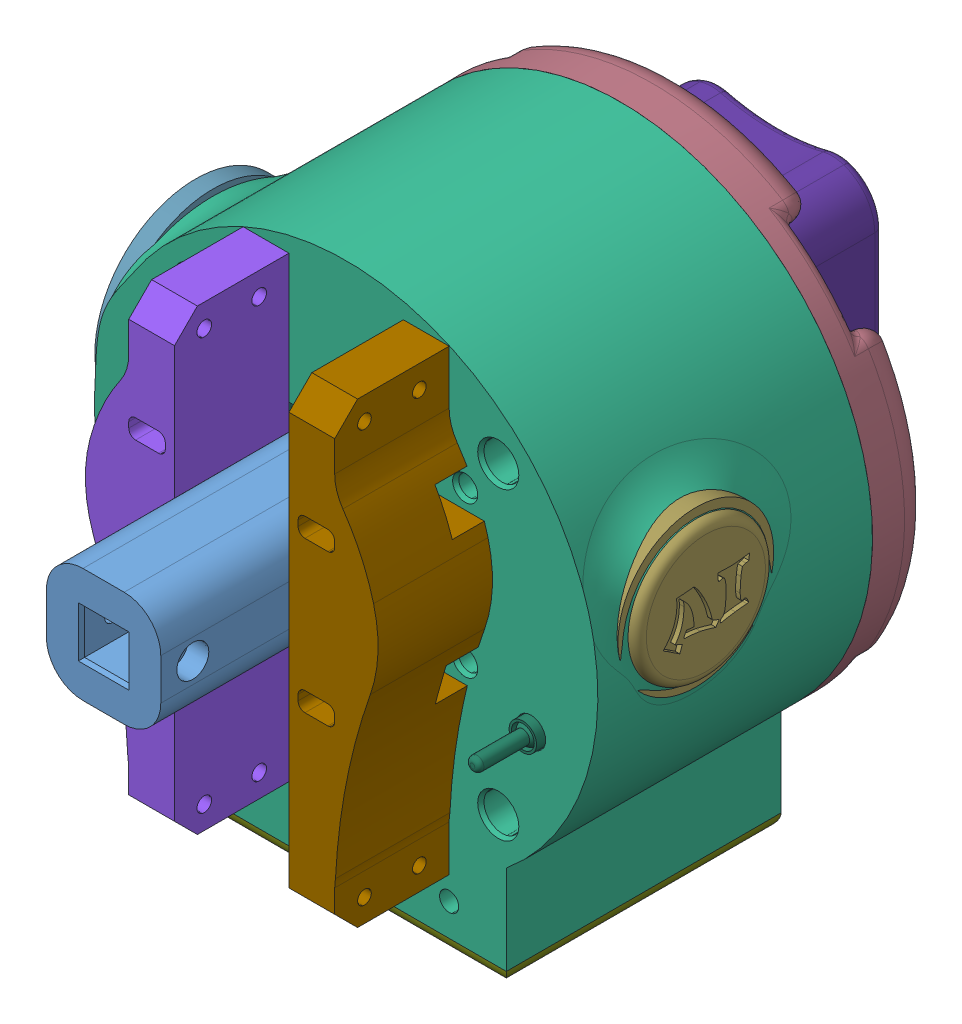
SolidWorks assembly clb00_CollectiveBaseI2C, configuration По умолчанию. Lengths in mm.
Overall size (115.55 120 148).
24 component instances, 17 part files, 56 mates.
Components (placement in the parent):
- clb03a_LeverConnector10mmRail-1: clb03a_LeverConnector10mmRail [По умолчанию] at (44.3103 52.5722 -4.4772) size (25 25 86)
- 608_bearing_v1-1: 608_bearing_v1 [По умолчанию] at (58.4103 52.5722 5.5228) x (0 -0.975622 0.219457) z (0 0.219457 0.975622) size (22 7.15 22)
- 608_bearing_v1-2: 608_bearing_v1 [По умолчанию] at (16.3103 52.5722 5.5228) x (0 -1 0) z (0 0 1) size (22 7.15 22)
- 608_bearing_v1-3: 608_bearing_v1 [По умолчанию] at (72.3103 52.5722 5.5228) x (0 1 0) z (0 0 1) size (22 7.15 22)
- 608_bearing_v1-4: 608_bearing_v1 [По умолчанию] at (30.2103 52.5722 5.5228) x (0 1 0) z (0 0 1) size (22 7.15 22)
- M8 washer_regular-1: M8 washer_regular [По умолчанию] at (31.8103 52.5722 5.5228) x (0 0 1) z (-1 0 0) size (15.8 15.8 1.5)
- M8 washer_regular-2: M8 washer_regular [По умолчанию] at (58.3103 52.5722 5.5228) x (0 0 1) z (-1 0 0) size (15.8 15.8 1.5)
- clb01_LeverFrameP1-3: clb01_LeverFrameP1 [По умолчанию] at (44.3103 52.5722 20.5228) x (1 0 0) z (0 1 0) size (78.5 15 68)
- M6x70mm-1: M6x70mm [По умолчанию] at (5.4103 52.5722 5.5228) x (0 -0.980406 -0.196989) z (0 -0.196989 0.980406) size (11.6 74.3 11.6)
- clb05_EnclosureWExtSlot-1: clb05_EnclosureWExtSlot [По умолчанию] at (44.3103 44.0722 -32.4772) x (0 1 0) z (1 0 0) size (117 62.47 113.55)
- clb02_LeverFrameP2-2: clb02_LeverFrameP2 [По умолчанию] at (44.3103 52.5722 -9.4772) x (-1 0 0) z (0 1 0) size (65 15 68)
- clb10_FrictionTensionerLeft-1: clb10_FrictionTensionerLeft [По умолчанию] at (21.8103 44.2222 27.5228) x (1 0 0) z (0 -1 0) size (19.47 25 100)
- clb11_FrictionTensionerRight-1: clb11_FrictionTensionerRight [По умолчанию] at (66.8103 44.1222 52.5228) x (-1 0 0) z (0 -1 0) size (19.47 25 100)
- 6x6x4mm_square-1: 6x6x4mm_square [По умолчанию] at (2.4103 49.5722 5.5228) size (6 6 4)
- M8 washer_regular-3: M8 washer_regular [По умолчанию] at (72.4103 52.5722 5.5228) x (0 0 -1) z (1 0 0) size (15.8 15.8 1.5)
- M8 washer_regular-4: M8 washer_regular [По умолчанию] at (75.4103 52.5722 5.5228) x (0 0 1) z (-1 0 0) size (15.8 15.8 1.5)
- clb04_LeverFrameCurtain-1: clb04_LeverFrameCurtain [По умолчанию] at (42.9159 43.7468 -9.4772) x (1 0 0) z (0 0 -1) size (65 54.8 2.4)
- clb08_CalibrationScrewLid-1: clb08_CalibrationScrewLid [По умолчанию] at (95.4103 52.0722 6.0228) x (0 0.9998 0.019984) z (0 0.019984 -0.9998) size (34 6 34)
- clb06_EnclosureBackI2C-1: clb06_EnclosureBackI2C [По умолчанию] at (44.3103 44.0722 -45.4772) x (0 1 0) z (1 0 0) size (110 19.51 110)
- clb07_EnclosureSensorLid-1: clb07_EnclosureSensorLid [По умолчанию] at (-6.7897 54.0722 5.5228) x (0 0.999914 0.013101) z (0 -0.013101 0.999914) size (44 6 44)
- MTS-103-1: MTS-103 [По умолчанию] at (3.9103 30.0722 11.0228) x (0 -1 0) z (-1 0 0) size (13.2 33.3 7.9)
- MTS-103-2: MTS-103 [По умолчанию] at (84.7103 30.0722 11.0228) x (0 1 0) z (1 0 0) size (13.2 33.3 7.9)
- clb09_ExtSlotLid-2: clb09_ExtSlotLid [По умолчанию] at (44.3103 4.0722 -2.4772) x (-1 0 0) z (0 0 1) size (70 25 60)
- clb12_RailMount-1: clb12_RailMount [По умолчанию] at (44.3103 44.0722 -45.4772) x (1 0 0) z (0 1 0) size (45 22 69.79)
Mates (geometry in assembly coordinates):
- Concentric1: concentric anti-aligned: cylinder of clb03a_LeverConnector10mmRail-1 through (56.8103 52.5722 5.5228) axis (-1 0 0) radius 3; cylinder of 608_bearing_v1-4 through (26.7353 52.5722 5.5228) axis (1 0 0) radius 4
- Concentric2: concentric anti-aligned: cylinder of 608_bearing_v1-2 through (19.7853 52.5722 5.5228) axis (-1 0 0) radius 4; cylinder of 608_bearing_v1-4 through (26.7353 52.5722 5.5228) axis (1 0 0) radius 4
- Coincident1: coincident anti-aligned: plane of 608_bearing_v1-2 through (23.2603 52.5722 5.5228) normal (1 0 0); plane of 608_bearing_v1-4 through (23.2603 52.5722 5.5228) normal (-1 0 0)
- Concentric3: concentric anti-aligned: cylinder of clb03a_LeverConnector10mmRail-1 through (56.8103 52.5722 5.5228) axis (-1 0 0) radius 3; cylinder of 608_bearing_v1-3 through (68.8353 52.5722 5.5228) axis (1 0 0) radius 4
- Concentric4: concentric anti-aligned: cylinder of 608_bearing_v1-1 through (61.8853 52.5722 5.5228) axis (-1 0 0) radius 4; cylinder of 608_bearing_v1-3 through (68.8353 52.5722 5.5228) axis (1 0 0) radius 4
- Coincident2: coincident anti-aligned: plane of 608_bearing_v1-1 through (65.3603 52.5722 5.5228) normal (1 0 0); plane of 608_bearing_v1-3 through (65.3603 52.5722 5.5228) normal (-1 0 0)
- Concentric6: concentric anti-aligned: cylinder of clb03a_LeverConnector10mmRail-1 through (56.8103 52.5722 5.5228) axis (-1 0 0) radius 3; cylinder of M8 washer_regular-2 through (56.8103 52.5722 5.5228) axis (1 0 0) radius 4.15
- Coincident5: coincident anti-aligned: plane of clb03a_LeverConnector10mmRail-1 through (56.8103 40.0722 80.5228) normal (1 0 0); plane of M8 washer_regular-2 through (56.8103 52.5722 5.5228) normal (-1 0 0)
- Concentric7: concentric anti-aligned: cylinder of clb03a_LeverConnector10mmRail-1 through (56.8103 52.5722 5.5228) axis (-1 0 0) radius 3; cylinder of M8 washer_regular-1 through (30.3103 52.5722 5.5228) axis (1 0 0) radius 4.15
- Coincident6: coincident anti-aligned: plane of clb03a_LeverConnector10mmRail-1 through (31.8103 40.0722 80.5228) normal (-1 0 0); plane of M8 washer_regular-1 through (31.8103 52.5722 5.5228) normal (1 0 0)
- Coincident7: coincident anti-aligned: plane of 608_bearing_v1-4 through (30.3103 52.5722 5.5228) normal (1 0 0); plane of M8 washer_regular-1 through (30.3103 52.5722 5.5228) normal (-1 0 0)
- Coincident8: coincident anti-aligned: plane of 608_bearing_v1-1 through (58.3103 52.5722 5.5228) normal (-1 0 0); plane of M8 washer_regular-2 through (58.3103 52.5722 5.5228) normal (1 0 0)
- Concentric10: concentric aligned: cylinder of 608_bearing_v1-2 through (19.7853 52.5722 5.5228) axis (-1 0 0) radius 11; cylinder of clb01_LeverFrameP1-3 through (58.3103 52.5722 5.5228) axis (-1 0 0) radius 11.1
- Coincident9: coincident anti-aligned: plane of 608_bearing_v1-2 through (16.3103 52.5722 5.5228) normal (-1 0 0); plane of clb01_LeverFrameP1-3 through (16.3103 63.6722 5.5228) normal (1 0 0)
- Angle4: planar angle = 0 rad anti-aligned: plane of clb03a_LeverConnector10mmRail-1 through (56.8103 65.0722 80.5228) normal (0 1 0); plane of clb01_LeverFrameP1-3 through (89.3722 65.3722 11.4363) normal (0 -1 0)
- Concentric14: concentric anti-aligned: cylinder of 608_bearing_v1-3 through (68.8353 52.5722 5.5228) axis (1 0 0) radius 4; cylinder of M6x70mm-1 through (75.4103 52.5722 5.5228) axis (-1 0 0) radius 3
- Parallel1: parallel anti-aligned: plane of clb03a_LeverConnector10mmRail-1 through (31.8103 40.0722 80.5228) normal (-1 0 0); plane of clb05_EnclosureWExtSlot-1 through (31.3103 23.4722 27.5228) normal (1 0 0)
- Coincident15: coincident anti-aligned: plane of clb01_LeverFrameP1-3 through (44.3103 52.5722 20.5228) normal (0 0 1); plane of clb05_EnclosureWExtSlot-1 through (44.3103 44.0722 20.5228) normal (0 0 -1)
- Concentric15: concentric aligned: cylinder of 608_bearing_v1-3 through (68.8353 52.5722 5.5228) axis (1 0 0) radius 11; cylinder of clb02_LeverFrameP2-2 through (30.3103 52.5722 5.5228) axis (1 0 0) radius 11.1
- Concentric16: concentric anti-aligned: cylinder of clb01_LeverFrameP1-3 through (18.3103 36.0722 20.5228) axis (0 0 -1) radius 2.15; cylinder of clb02_LeverFrameP2-2 through (18.3103 36.0722 -9.4772) axis (0 0 1) radius 2.15
- Coincident18: coincident anti-aligned: plane of clb03a_LeverConnector10mmRail-1 through (31.8103 40.0722 80.5228) normal (-1 0 0); plane of clb10_FrictionTensionerLeft-1 through (31.8103 -5.7778 52.5228) normal (1 0 0)
- Coincident19: coincident anti-aligned: plane of clb05_EnclosureWExtSlot-1 through (44.3103 44.0722 27.5228) normal (0 0 1); plane of clb10_FrictionTensionerLeft-1 through (21.8103 44.2222 27.5228) normal (0 0 -1)
- Tangent1: tangent anti-aligned: cylinder of clb05_EnclosureWExtSlot-1 through (26.3103 36.0722 -32.4772) axis (0 0 1) radius 2.25; plane of clb10_FrictionTensionerLeft-1 through (29.8103 38.3222 52.5228) normal (0 -1 0)
- Concentric18: concentric aligned: cylinder of clb05_EnclosureWExtSlot-1 through (18.3103 69.0722 -32.4772) axis (0 0 1) radius 2.25; cylinder of clb02_LeverFrameP2-2 through (18.3103 69.0722 -9.4772) axis (0 0 1) radius 2.15
- Coincident20: coincident anti-aligned: plane of clb05_EnclosureWExtSlot-1 through (44.3103 44.0722 27.5228) normal (0 0 1); plane of clb11_FrictionTensionerRight-1 through (66.8103 44.1222 27.5228) normal (0 0 -1)
- Coincident21: coincident anti-aligned: plane of clb03a_LeverConnector10mmRail-1 through (56.8103 40.0722 80.5228) normal (1 0 0); plane of clb11_FrictionTensionerRight-1 through (56.8103 -5.8778 27.5228) normal (-1 0 0)
- Tangent2: tangent anti-aligned: cylinder of clb01_LeverFrameP1-3 through (62.3103 36.0722 20.5228) axis (0 0 -1) radius 2.15; plane of clb11_FrictionTensionerRight-1 through (58.8103 38.2222 27.5228) normal (0 -1 0)
- Coincident23: coincident anti-aligned: plane of M6x70mm-1 through (5.4103 52.5722 5.5228) normal (-1 0 0); plane of 6x6x4mm_square-1 through (5.4103 55.5722 7.5228) normal (1 0 0)
- Concentric21: concentric anti-aligned: cylinder of M6x70mm-1 through (75.4103 52.5722 5.5228) axis (-1 0 0) radius 3; cylinder of 6x6x4mm_square-1 through (4.4103 52.5722 5.5228) axis (1 0 0) radius 1.5
- Concentric22: concentric anti-aligned: cylinder of M6x70mm-1 through (75.4103 52.5722 5.5228) axis (-1 0 0) radius 3; cylinder of M8 washer_regular-4 through (73.9103 52.5722 5.5228) axis (1 0 0) radius 4.15
- Concentric23: concentric anti-aligned: cylinder of M8 washer_regular-3 through (73.9103 52.5722 5.5228) axis (-1 0 0) radius 4.15; cylinder of M8 washer_regular-4 through (73.9103 52.5722 5.5228) axis (1 0 0) radius 4.15
- Coincident24: coincident anti-aligned: plane of M8 washer_regular-3 through (73.9103 52.5722 5.5228) normal (1 0 0); plane of M8 washer_regular-4 through (73.9103 52.5722 5.5228) normal (-1 0 0)
- Coincident25: coincident anti-aligned: plane of 608_bearing_v1-3 through (72.4103 52.5722 5.5228) normal (1 0 0); plane of M8 washer_regular-3 through (72.4103 52.5722 5.5228) normal (-1 0 0)
- Coincident26: coincident anti-aligned: plane of M6x70mm-1 through (75.4103 52.5722 5.5228) normal (-1 0 0); plane of M8 washer_regular-4 through (75.4103 52.5722 5.5228) normal (1 0 0)
- Concentric28: concentric aligned: cylinder of clb02_LeverFrameP2-2 through (18.3103 21.0722 -9.4772) axis (0 0 1) radius 2.15; cylinder of clb04_LeverFrameCurtain-1 through (18.3103 21.0722 -11.8772) axis (0 0 1) radius 2.15
- Concentric29: concentric aligned: cylinder of clb02_LeverFrameP2-2 through (70.3103 21.0722 -9.4772) axis (0 0 1) radius 2.15; cylinder of clb04_LeverFrameCurtain-1 through (70.3103 21.0722 -11.8772) axis (0 0 1) radius 2.15
- Coincident28: coincident anti-aligned: plane of clb02_LeverFrameP2-2 through (44.3103 52.5722 -9.4772) normal (0 0 -1); plane of clb04_LeverFrameCurtain-1 through (42.9159 43.7468 -9.4772) normal (0 0 1)
- Concentric40: concentric aligned: cylinder of clb05_EnclosureWExtSlot-1 through (44.3103 44.0722 17.5228) axis (0 0 -1) radius 50; cylinder of clb06_EnclosureBackI2C-1 through (44.3103 44.0722 -32.4772) axis (0 0 -1) radius 55
- Concentric41: concentric anti-aligned: cylinder of clb05_EnclosureWExtSlot-1 through (77.5444 10.8382 -32.4772) axis (0 0 1) radius 4; cylinder of clb06_EnclosureBackI2C-1 through (77.5444 10.8382 -27.4772) axis (0 0 -1) radius 4.1
- Coincident45: coincident anti-aligned: plane of clb05_EnclosureWExtSlot-1 through (44.3103 44.0722 -32.4772) normal (0 0 -1); plane of clb06_EnclosureBackI2C-1 through (44.3103 44.0722 -32.4772) normal (0 0 1)
- Concentric42: concentric aligned: cylinder of clb05_EnclosureWExtSlot-1 through (99.3103 52.0722 6.0228) axis (-1 0 0) radius 12.5; cylinder of clb08_CalibrationScrewLid-1 through (99.4103 52.0722 6.0228) axis (-1 0 0) radius 12.3
- Coincident47: coincident anti-aligned: plane of clb05_EnclosureWExtSlot-1 through (99.4103 52.0722 6.0228) normal (1 0 0); plane of clb08_CalibrationScrewLid-1 through (99.4103 52.0722 6.0228) normal (-1 0 0)
- Concentric44: concentric anti-aligned: cylinder of clb05_EnclosureWExtSlot-1 through (11.3103 54.0722 5.5228) axis (-1 0 0) radius 17.5; cylinder of clb07_EnclosureSensorLid-1 through (-10.7897 54.0722 5.5228) axis (1 0 0) radius 17.3
- Coincident48: coincident anti-aligned: plane of clb05_EnclosureWExtSlot-1 through (-10.7897 54.0722 5.5228) normal (-1 0 0); plane of clb07_EnclosureSensorLid-1 through (-10.7897 54.0722 5.5228) normal (1 0 0)
- Concentric45: concentric aligned: cylinder of clb05_EnclosureWExtSlot-1 through (3.9103 30.0722 29.9925) axis (0 0 -1) radius 3.2; cylinder of MTS-103-1 through (3.9103 30.0722 29.3228) axis (0 0 -1) radius 3
- Concentric46: concentric aligned: cylinder of clb05_EnclosureWExtSlot-1 through (84.7103 30.0722 29.9925) axis (0 0 -1) radius 3.2; cylinder of MTS-103-2 through (84.7103 30.0722 29.3228) axis (0 0 -1) radius 3
- Coincident49: coincident anti-aligned: plane of clb05_EnclosureWExtSlot-1 through (44.3103 44.0722 20.5228) normal (0 0 -1); plane of MTS-103-2 through (84.7103 30.0722 20.5228) normal (0 0 1)
- Parallel2: parallel anti-aligned: plane of clb05_EnclosureWExtSlot-1 through (89.2103 37.0722 -32.4772) normal (-1 0 0); plane of MTS-103-2 through (88.6603 36.6722 20.5228) normal (1 0 0)
- Coincident51: coincident anti-aligned: plane of clb05_EnclosureWExtSlot-1 through (44.3103 44.0722 20.5228) normal (0 0 -1); plane of MTS-103-1 through (3.9103 30.0722 20.5228) normal (0 0 1)
- Parallel3: parallel aligned: plane of clb01_LeverFrameP1-3 through (11.8103 102.5722 5.5228) normal (-1 0 0); plane of MTS-103-1 through (-0.0397 23.4722 20.5228) normal (-1 0 0)
- Coincident55: coincident anti-aligned: plane of clb05_EnclosureWExtSlot-1 through (44.3103 -17.9278 -32.4772) normal (0 -1 0); plane of clb09_ExtSlotLid-2 through (44.3103 -17.9278 -2.4772) normal (0 1 0)
- Coincident56: coincident aligned: line of clb05_EnclosureWExtSlot-1 through (9.3103 -17.9278 27.5228) axis (0 0 -1); line of clb09_ExtSlotLid-2 through (9.3103 -17.9278 27.5228) axis (0 0 -1)
- Coincident57: coincident aligned: line of clb05_EnclosureWExtSlot-1 through (9.3103 -17.9278 -32.4772) axis (1 0 0); line of clb09_ExtSlotLid-2 through (9.3103 -17.9278 -32.4772) axis (1 0 0)
- Concentric47: concentric anti-aligned: cylinder of clb06_EnclosureBackI2C-1 through (29.3103 19.0722 -27.4772) axis (0 0 -1) radius 4.15; cylinder of clb12_RailMount-1 through (29.3103 19.0722 -67.4772) axis (0 0 1) radius 4.2
- Concentric50: concentric anti-aligned: cylinder of clb06_EnclosureBackI2C-1 through (59.3103 69.0722 -27.4772) axis (0 0 -1) radius 4.15; cylinder of clb12_RailMount-1 through (59.3103 69.0722 -67.4772) axis (0 0 1) radius 4.2
- Coincident58: coincident anti-aligned: plane of clb06_EnclosureBackI2C-1 through (44.3103 44.0722 -45.4772) normal (0 0 -1); plane of clb12_RailMount-1 through (44.3103 44.0722 -45.4772) normal (0 0 1)
